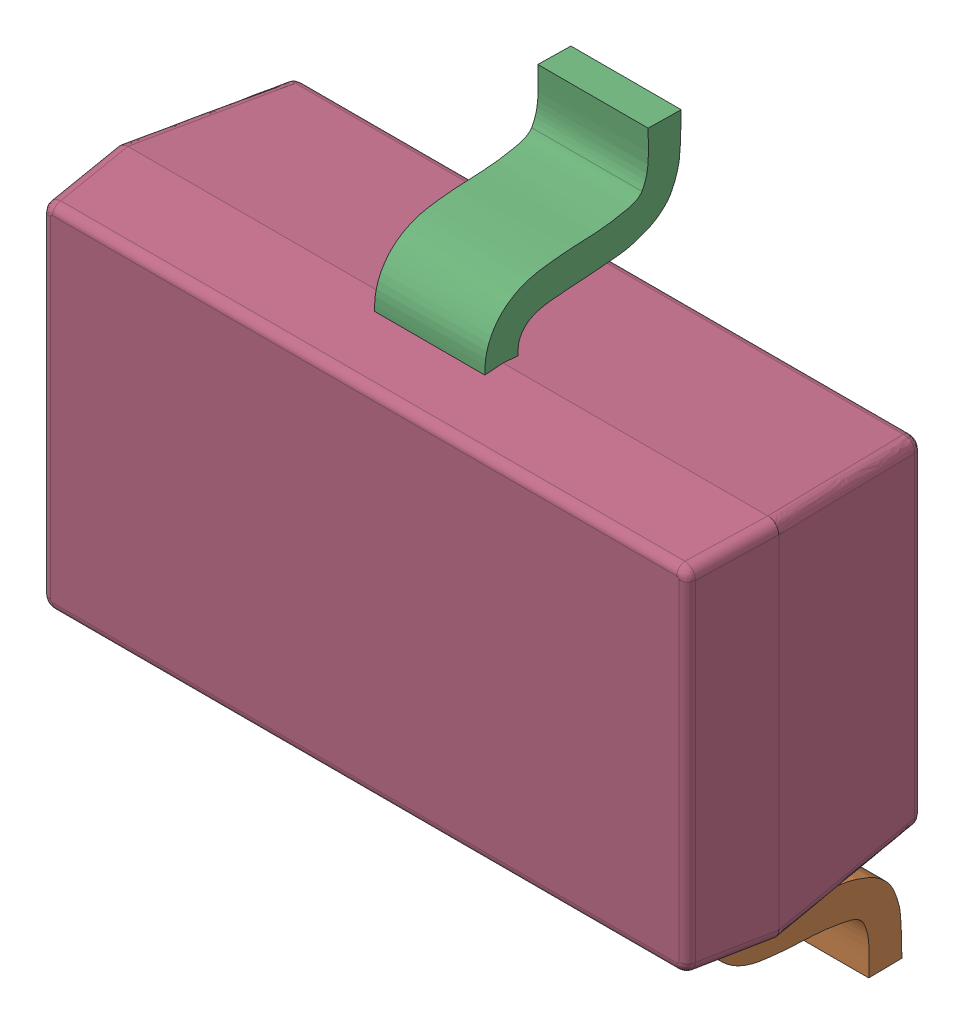
SolidWorks assembly U1, configuration Default. Lengths in mm.
Overall size (3.01 2.91 1.23).
3 component instances, 2 part files, 0 mates.
Components (placement in the parent):
- SOT23-3-1: SOT23-3 [Default] at (15.3909 26.7763 0) x (0 -1 0) z (0 0 1) size (2.91 3.01 1.23)
- 4438511424-1: 4438511424 [Default] at (15.494 27.051 0) size (0.25 0.25 0.25)
  - Extruded-1: Extruded [Default] at origin size (0.25 0.25 0.25)
